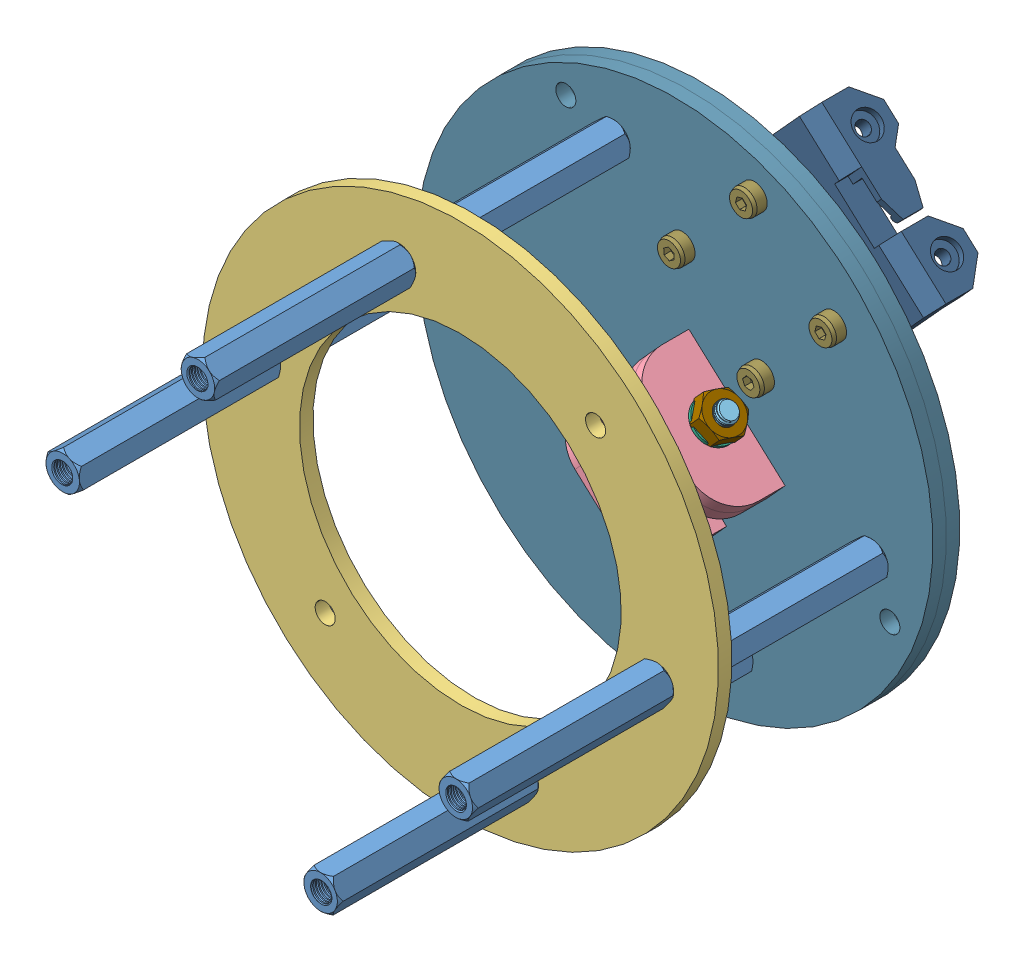
SolidWorks assembly RobotBaseAX12, configuration Default. Lengths in mm.
Overall size (108.77 108.77 76.29).
45 component instances, 15 part files, 103 mates.
Components (placement in the parent):
- M3Spacer30-1: M3Spacer30 [Default] at (4.7282 -17.4075 3.4562) x (0.207823 -0.978166 0) z (-0.978166 -0.207823 0) size (6.28 30.59 5)
- M3ThreadRod-1: M3ThreadRod [Default] at (4.7282 -17.4075 23.9562) x (0.200571 -0.979679 0) z (-0.979679 -0.200571 0) size (3.13 20.14 3.46)
- MiddlePlate-1: MiddlePlate [Default] at (-4.4212 11.1633 35.4562) x (0.672277 0.7403 0) z (0 0 -1) size (77 77 2)
- M3ThreadRod-2: M3ThreadRod [Default] at (-33.7389 17.525 23.9562) x (0.697343 -0.716737 0) z (-0.716737 -0.697343 0) size (3.13 20.14 3.46)
- M3ThreadRod-3: M3ThreadRod [Default] at (-13.5706 39.734 23.9562) x (0.867995 0.496573 0) z (0.496573 -0.867995 0) size (3.13 20.14 3.46)
- M3ThreadRod-4: M3ThreadRod [Default] at (24.8965 4.8015 23.9562) x (0.97301 -0.230763 0) z (-0.230763 -0.97301 0) size (3.13 20.14 3.46)
- M3Spacer30-2: M3Spacer30 [Default] at (-13.5706 39.734 3.4562) x (0.207823 -0.978166 0) z (-0.978166 -0.207823 0) size (6.28 30.59 5)
- M3Spacer30-3: M3Spacer30 [Default] at (-33.7389 17.525 3.4562) x (0.207823 -0.978166 0) z (-0.978166 -0.207823 0) size (6.28 30.59 5)
- M3Spacer30-4: M3Spacer30 [Default] at (24.8965 4.8015 3.4562) x (0.207823 -0.978166 0) z (-0.978166 -0.207823 0) size (6.28 30.59 5)
- M3Spacer30-5: M3Spacer30 [Default] at (-33.7389 17.525 35.4562) x (-0.803339 -0.595522 0) z (-0.595522 0.803339 0) size (6.28 30.59 5)
- M3Spacer30-6: M3Spacer30 [Default] at (-13.5706 39.734 35.4562) x (-0.94995 -0.312401 0) z (-0.312401 0.94995 0) size (6.28 30.59 5)
- M3Spacer30-7: M3Spacer30 [Default] at (24.8965 4.8015 35.4562) x (0.47318 -0.880966 0) z (-0.880966 -0.47318 0) size (6.28 30.59 5)
- M3Spacer30-8: M3Spacer30 [Default] at (4.7282 -17.4075 35.4562) x (0.999987 -0.005046 0) z (-0.005046 -0.999987 0) size (6.28 30.59 5)
- BearingBase-1: BearingBase [Default] at (-3.893 4.605 6.9562) x (0.7403 -0.672277 0) z (-0.672277 -0.7403 0) size (19.4 14 2)
- BearingBase-2: BearingBase [Default] at (-5.2375 3.1244 6.9562) x (0.7403 -0.672277 0) z (-0.672277 -0.7403 0) size (19.4 14 2)
- BearingBase-3: BearingBase [Default] at (3.5021 12.7483 6.9562) x (-0.7403 0.672277 0) z (0.672277 0.7403 0) size (19.4 14 2)
- BearingBase-4: BearingBase [Default] at (2.1575 11.2677 6.9562) x (-0.7403 0.672277 0) z (0.672277 0.7403 0) size (19.4 14 2)
- M3x20-1: M3x20 [Default] at (-6.5821 1.6438 6.9562) x (-0.399144 0.362469 -0.8422) z (-0.62348 0.566192 0.539166) size (5.5 23.77 5.5)
- M3Washer-1: M3Washer [Default] at (-2.5484 6.0856 6.9562) x (-0.730674 0.663536 0.160736) z (-0.118993 0.108059 -0.986997) size (6 0.5 6)
- PlasticSpacer-1: PlasticSpacer [Default] at (-2.5484 6.0856 6.9562) x (-0.284902 0.258724 -0.92298) z (-0.683282 0.620498 0.384847) size (6 2 6)
- pulley-1: pulley [Default] at (0.4768 9.4169 6.9562) x (-0.418707 0.380234 0.824686) z (0.610515 -0.554418 0.565591) size (12 4 12)
- M3Washer-2: M3Washer [Default] at (0.4768 9.4169 6.9562) x (0.735393 -0.667821 -0.114942) z (0.085091 -0.077273 0.993372) size (6 0.5 6)
- PlasticSpacer-3: PlasticSpacer [Default] at (2.1575 11.2677 6.9562) x (0.683126 -0.620357 -0.385352) z (-0.285276 0.259063 -0.92277) size (6 2 6)
- M3Nut-1: M3Nut [Default] at (4.8466 14.2289 6.9562) x (0.508771 -0.462022 0.726421) z (-0.53777 0.488356 0.68725) size (6.35 2.7 5.5)
- M3Washer-3: M3Washer [Default] at (4.8466 14.2289 6.9562) x (0.506448 -0.459913 -0.729377) z (0.539957 -0.490343 0.684112) size (6 0.5 6)
- AX12Base-1: AX12Base [Default] at (7.9887 31.5224 -0.5438) x (-0.7403 0.672277 0) z (-0.672277 -0.7403 0) size (25 9 38)
- M2Nut-1: M2Nut [Default] at (7.4445 42.823 -4.5438) x (-0.340986 0.940068 0) z (0.940068 0.340986 0) size (4.58 1.66 4.98)
- M2x8-1: M2x8 [Default] at (7.4445 42.823 3.4562) x (-0.96159 -0.27449 0) z (-0.27449 0.96159 0) size (3.8 10 3.8)
- M2Nut-2: M2Nut [Default] at (8.5328 20.2218 -4.5438) x (0.64363 0.765337 0) z (0.765337 -0.64363 0) size (4.58 1.66 4.98)
- M2Nut-3: M2Nut [Default] at (-3.312 30.9782 -4.5438) x (0.64363 0.765337 0) z (0.765337 -0.64363 0) size (4.58 1.66 4.98)
- M2Nut-4: M2Nut [Default] at (19.2893 32.0666 -4.5438) x (0.64363 0.765337 0) z (0.765337 -0.64363 0) size (4.58 1.66 4.98)
- M2x8-2: M2x8 [Default] at (8.5328 20.2218 3.4562) x (-0.634736 -0.772729 0) z (-0.772729 0.634736 0) size (3.8 10 3.8)
- M2x8-3: M2x8 [Default] at (-3.312 30.9782 3.4562) x (0.897196 -0.441632 0) z (-0.441632 -0.897196 0) size (3.8 10 3.8)
- M2x8-4: M2x8 [Default] at (19.2893 32.0666 3.4562) x (0.715995 -0.698105 0) z (-0.698105 -0.715995 0) size (3.8 10 3.8)
- M3Washer-4: M3Washer [Default] at (4.7282 -17.4075 -0.5438) x (-0.207823 0.978166 0) z (-0.978166 -0.207823 0) size (6 0.5 6)
- M3x10-1: M3x10 [Default] at (4.7282 -17.4075 -1.0438) x (0.990322 -0.138791 0) z (0.138791 0.990322 0) size (5.5 13.21 5.5)
- M3x10-2: M3x10 [Default] at (-13.5706 39.734 -1.0438) x (-0.982342 -0.187094 0) z (0.187094 -0.982342 0) size (5.5 13.21 5.5)
- M3x10-3: M3x10 [Default] at (-33.7389 17.525 -1.0438) x (-0.885366 0.464894 0) z (-0.464894 -0.885366 0) size (5.5 13.21 5.5)
- M3x10-4: M3x10 [Default] at (24.8965 4.8015 -1.0438) x (-0.753911 0.656976 0) z (-0.656976 -0.753911 0) size (5.5 13.21 5.5)
- M3Washer-5: M3Washer [Default] at (24.8965 4.8015 -0.5438) x (-0.207823 0.978166 0) z (-0.978166 -0.207823 0) size (6 0.5 6)
- M3Washer-6: M3Washer [Default] at (-13.5706 39.734 -0.5438) x (-0.207823 0.978166 0) z (-0.978166 -0.207823 0) size (6 0.5 6)
- M3Washer-7: M3Washer [Default] at (-33.7389 17.525 -0.5438) x (-0.207823 0.978166 0) z (-0.978166 -0.207823 0) size (6 0.5 6)
- BottomPlateAX12-1: BottomPlateAX12 [Default] at (-4.4755 11.2126 -0.5438) x (0.672277 0.7403 0) z (0 0 1) size (77 77 2)
- BottomPlateAX12-2: BottomPlateAX12 [Default] at (-4.4755 11.2126 1.4562) x (0.672277 0.7403 0) z (0 0 1) size (77 77 2)
- PCBMount-1: PCBMount [Default] at (-18.642 5.8415 -7.5438) x (0.7403 -0.672277 0) z (0.672277 0.7403 0) size (31.5 14 2)
Mates (geometry in assembly coordinates):
- Concentric1: concentric anti-aligned: circle of M3Spacer30-1; circle of MiddlePlate-1
- Concentric2: concentric anti-aligned: circle of MiddlePlate-1; circle of M3Spacer30-4
- Concentric3: concentric anti-aligned: circle of MiddlePlate-1; circle of M3Spacer30-3
- Concentric4: concentric anti-aligned: circle of MiddlePlate-1; circle of M3Spacer30-2
- Concentric5: concentric aligned: circle of M3ThreadRod-4; circle of M3Spacer30-4
- Concentric7: concentric anti-aligned: circle of M3ThreadRod-3; circle of M3Spacer30-2
- Concentric8: concentric aligned: circle of M3ThreadRod-2; circle of M3Spacer30-3
- Concentric9: concentric aligned: circle of M3Spacer30-1; circle of M3ThreadRod-1
- Distance5: distance = 10 mm aligned: plane of M3ThreadRod-1 through (4.7282 -17.4075 43.4562) normal (0 0 1); plane of M3Spacer30-1 through (4.7282 -17.4075 33.4562) normal (0 0 1)
- Distance6: distance = 10 mm aligned: plane of M3ThreadRod-2 through (-33.7389 17.525 43.4562) normal (0 0 1); plane of M3Spacer30-3 through (-33.7389 17.525 33.4562) normal (0 0 1)
- Distance7: distance = 10 mm aligned: plane of M3ThreadRod-3 through (-13.5706 39.734 43.4562) normal (0 0 1); plane of M3Spacer30-2 through (-13.5706 39.734 33.4562) normal (0 0 1)
- Distance8: distance = 10 mm aligned: plane of M3ThreadRod-4 through (24.8965 4.8015 43.4562) normal (0 0 1); plane of M3Spacer30-4 through (24.8965 4.8015 33.4562) normal (0 0 1)
- Coincident3: coincident anti-aligned: plane of M3Spacer30-1 through (4.7282 -17.4075 33.4562) normal (0 0 1); plane of MiddlePlate-1 through (-4.4212 11.1633 33.4562) normal (0 0 -1)
- Coincident4: coincident anti-aligned: plane of MiddlePlate-1 through (-4.4212 11.1633 33.4562) normal (0 0 -1); plane of M3Spacer30-4 through (24.8965 4.8015 33.4562) normal (0 0 1)
- Coincident5: coincident anti-aligned: plane of MiddlePlate-1 through (-4.4212 11.1633 33.4562) normal (0 0 -1); plane of M3Spacer30-2 through (-13.5706 39.734 33.4562) normal (0 0 1)
- Coincident6: coincident anti-aligned: plane of MiddlePlate-1 through (-4.4212 11.1633 33.4562) normal (0 0 -1); plane of M3Spacer30-3 through (-33.7389 17.525 33.4562) normal (0 0 1)
- Concentric10: concentric aligned: circle of M3ThreadRod-2; circle of M3Spacer30-5
- Concentric11: concentric aligned: circle of M3ThreadRod-3; circle of M3Spacer30-6
- Concentric12: concentric aligned: circle of M3ThreadRod-4; circle of M3Spacer30-7
- Concentric13: concentric aligned: circle of M3ThreadRod-1; circle of M3Spacer30-8
- Coincident8: coincident anti-aligned: plane of MiddlePlate-1 through (-4.4212 11.1633 35.4562) normal (0 0 1); plane of M3Spacer30-5 through (-33.7389 17.525 35.4562) normal (0 0 -1)
- Coincident9: coincident anti-aligned: plane of MiddlePlate-1 through (-4.4212 11.1633 35.4562) normal (0 0 1); plane of M3Spacer30-6 through (-13.5706 39.734 35.4562) normal (0 0 -1)
- Coincident10: coincident anti-aligned: plane of MiddlePlate-1 through (-4.4212 11.1633 35.4562) normal (0 0 1); plane of M3Spacer30-7 through (24.8965 4.8015 35.4562) normal (0 0 -1)
- Coincident11: coincident anti-aligned: plane of MiddlePlate-1 through (-4.4212 11.1633 35.4562) normal (0 0 1); plane of M3Spacer30-8 through (4.7282 -17.4075 35.4562) normal (0 0 -1)
- Parallel3: parallel aligned: plane of BearingBase-1 through (-2.4984 0.637 7.4562) normal (-0.672277 -0.7403 0); plane of BearingBase-2 through (-3.843 -0.8436 7.4562) normal (-0.672277 -0.7403 0)
- Concentric18: concentric aligned: circle of BearingBase-1; circle of BearingBase-2
- Coincident14: coincident anti-aligned: plane of BearingBase-1 through (-2.4984 0.637 7.4562) normal (-0.672277 -0.7403 0); plane of BearingBase-2 through (-2.4984 0.637 7.4562) normal (0.672277 0.7403 0)
- Coincident16: coincident: point of BearingBase-1; point of BearingBase-2
- Concentric19: concentric aligned: circle of BearingBase-3; circle of BearingBase-4
- Coincident18: coincident: point of BearingBase-3; point of BearingBase-4
- Concentric21: concentric aligned: circle of BearingBase-2; circle of M3x20-1
- Coincident22: coincident anti-aligned: plane of BearingBase-2 through (-3.843 -0.8436 7.4562) normal (-0.672277 -0.7403 0); plane of M3x20-1 through (-6.5821 1.6438 6.9562) normal (0.672277 0.7403 0)
- Concentric22: concentric aligned: circle of M3x20-1; circle of PlasticSpacer-1
- Coincident23: coincident anti-aligned: plane of BearingBase-1 through (-1.1539 2.1176 7.4562) normal (0.672277 0.7403 0); plane of PlasticSpacer-1 through (-3.893 4.605 6.9562) normal (-0.672277 -0.7403 0)
- Concentric23: concentric anti-aligned: circle of M3Washer-1; circle of PlasticSpacer-1
- Coincident25: coincident anti-aligned: plane of M3Washer-1 through (-2.5484 6.0856 6.9562) normal (-0.672277 -0.7403 0); plane of PlasticSpacer-1 through (-2.5484 6.0856 6.9562) normal (0.672277 0.7403 0)
- Concentric24: concentric anti-aligned: circle of M3Washer-1; circle of pulley-1
- Coincident26: coincident anti-aligned: plane of M3Washer-1 through (-2.2123 6.4557 6.9562) normal (0.672277 0.7403 0); plane of pulley-1 through (-2.2123 6.4557 6.9562) normal (-0.672277 -0.7403 0)
- Concentric25: concentric anti-aligned: circle of pulley-1; circle of M3Washer-2
- Coincident27: coincident anti-aligned: plane of pulley-1 through (0.4768 9.4169 6.9562) normal (0.672277 0.7403 0); plane of M3Washer-2 through (0.4768 9.4169 6.9562) normal (-0.672277 -0.7403 0)
- Concentric26: concentric aligned: circle of pulley-1; circle of PlasticSpacer-3
- Coincident28: coincident anti-aligned: plane of M3Washer-2 through (0.813 9.7871 6.9562) normal (0.672277 0.7403 0); plane of PlasticSpacer-3 through (0.813 9.7871 6.9562) normal (-0.672277 -0.7403 0)
- Concentric27: concentric anti-aligned: circle of BearingBase-4; circle of PlasticSpacer-3
- Concentric28: concentric anti-aligned: circle of pulley-1; circle of M3Nut-1
- Concentric29: concentric anti-aligned: circle of pulley-1; circle of M3Washer-3
- Coincident33: coincident anti-aligned: plane of BearingBase-4 through (-0.5816 13.7551 7.4562) normal (-0.672277 -0.7403 0); plane of PlasticSpacer-3 through (2.1575 11.2677 6.9562) normal (0.672277 0.7403 0)
- Coincident34: coincident anti-aligned: plane of BearingBase-3 through (2.1075 16.7163 7.4562) normal (0.672277 0.7403 0); plane of M3Washer-3 through (4.8466 14.2289 6.9562) normal (-0.672277 -0.7403 0)
- Coincident35: coincident anti-aligned: plane of BearingBase-3 through (2.1075 16.7163 7.4562) normal (0.672277 0.7403 0); plane of M3Nut-1 through (4.8466 14.2289 6.9562) normal (-0.672277 -0.7403 0)
- Concentric37: concentric aligned: circle of AX12Base-1; circle of M2Nut-2
- Concentric38: concentric aligned: circle of AX12Base-1; circle of M2Nut-4
- Concentric39: concentric aligned: circle of AX12Base-1; circle of M2Nut-3
- Concentric40: concentric aligned: circle of AX12Base-1; circle of M2Nut-1
- Coincident42: coincident anti-aligned: plane of AX12Base-1 through (-5.0216 32.5308 -4.5438) normal (0.977257 -0.212059 0); plane of M2Nut-3 through (-5.0216 32.5308 -3.0438) normal (-0.977257 0.212059 0)
- Coincident43: coincident anti-aligned: plane of AX12Base-1 through (5.7348 44.3756 -4.5438) normal (0.30498 -0.952359 0); plane of M2Nut-1 through (7.9342 45.0799 -3.0438) normal (-0.30498 0.952359 0)
- Coincident44: coincident anti-aligned: plane of AX12Base-1 through (20.9989 30.514 -4.5438) normal (-0.977257 0.212059 0); plane of M2Nut-4 through (20.9989 30.514 -3.0438) normal (0.977257 -0.212059 0)
- Coincident45: coincident anti-aligned: plane of AX12Base-1 through (8.0431 17.9649 -4.5438) normal (-0.30498 0.952359 0); plane of M2Nut-2 through (8.0431 17.9649 -3.0438) normal (0.30498 -0.952359 0)
- Coincident46: coincident anti-aligned: plane of AX12Base-1 through (-4.5319 34.7877 -3.0438) normal (0 0 -1); plane of M2Nut-3 through (-3.312 30.9782 -3.0438) normal (0 0 1)
- Coincident47: coincident anti-aligned: plane of AX12Base-1 through (7.9342 45.0799 -3.0438) normal (0 0 -1); plane of M2Nut-1 through (7.4445 42.823 -3.0438) normal (0 0 1)
- Coincident48: coincident anti-aligned: plane of AX12Base-1 through (21.4887 32.7709 -3.0438) normal (0 0 -1); plane of M2Nut-4 through (19.2893 32.0666 -3.0438) normal (0 0 1)
- Coincident49: coincident anti-aligned: plane of AX12Base-1 through (10.7322 20.9261 -3.0438) normal (0 0 -1); plane of M2Nut-2 through (8.5328 20.2218 -3.0438) normal (0 0 1)
- Concentric41: concentric aligned: circle of M3x10-2; circle of M3Washer-6
- Concentric42: concentric aligned: circle of M3Washer-4; circle of M3x10-1
- Concentric43: concentric aligned: circle of M3x10-4; circle of M3Washer-5
- Concentric44: concentric aligned: circle of M3x10-3; circle of M3Washer-7
- Coincident63: coincident anti-aligned: plane of M3x10-2 through (-13.5706 39.734 -1.0438) normal (0 0 1); plane of M3Washer-6 through (-13.5706 39.734 -1.0438) normal (0 0 -1)
- Coincident64: coincident anti-aligned: plane of M3x10-4 through (24.8965 4.8015 -1.0438) normal (0 0 1); plane of M3Washer-5 through (24.8965 4.8015 -1.0438) normal (0 0 -1)
- Coincident65: coincident anti-aligned: plane of M3Washer-4 through (4.7282 -17.4075 -1.0438) normal (0 0 -1); plane of M3x10-1 through (4.7282 -17.4075 -1.0438) normal (0 0 1)
- Coincident66: coincident anti-aligned: plane of M3x10-3 through (-33.7389 17.525 -1.0438) normal (0 0 1); plane of M3Washer-7 through (-33.7389 17.525 -1.0438) normal (0 0 -1)
- Parallel4: parallel anti-aligned: plane of BottomPlateAX12-1 through (-4.4212 11.1633 1.4562) normal (0 0 1); plane of BottomPlateAX12-2 through (-4.4212 11.1633 1.4562) normal (0 0 -1)
- Concentric45: concentric aligned: circle of BottomPlateAX12-1; circle of BottomPlateAX12-2
- Concentric46: concentric aligned: circle of BottomPlateAX12-1; circle of BottomPlateAX12-2
- Coincident69: coincident anti-aligned: plane of BottomPlateAX12-1 through (-4.4212 11.1633 1.4562) normal (0 0 1); plane of BottomPlateAX12-2 through (-4.4212 11.1633 1.4562) normal (0 0 -1)
- Parallel5: parallel anti-aligned: plane of MiddlePlate-1 through (-4.4212 11.1633 33.4562) normal (0 0 -1); plane of BottomPlateAX12-2 through (-4.4212 11.1633 3.4562) normal (0 0 1)
- Concentric47: concentric anti-aligned: circle of AX12Base-1; circle of BottomPlateAX12-2
- Concentric48: concentric aligned: circle of AX12Base-1; circle of BottomPlateAX12-2
- Coincident72: coincident anti-aligned: plane of AX12Base-1 through (27.2945 31.2132 -0.5438) normal (0 0 1); plane of BottomPlateAX12-1 through (-4.4212 11.1633 -0.5438) normal (0 0 -1)
- Concentric50: concentric aligned: circle of M2x8-3; circle of BottomPlateAX12-2
- Concentric51: concentric aligned: circle of AX12Base-1; circle of M2x8-2
- Concentric52: concentric aligned: circle of M2x8-4; circle of BottomPlateAX12-2
- Coincident73: coincident anti-aligned: plane of M2x8-3 through (-3.312 30.9782 3.4562) normal (0 0 -1); plane of BottomPlateAX12-2 through (-4.4212 11.1633 3.4562) normal (0 0 1)
- Coincident75: coincident anti-aligned: plane of M2x8-4 through (19.2893 32.0666 3.4562) normal (0 0 -1); plane of BottomPlateAX12-2 through (-4.4212 11.1633 3.4562) normal (0 0 1)
- Concentric53: concentric anti-aligned: circle of AX12Base-1; circle of M2x8-1
- Coincident76: coincident anti-aligned: plane of M2x8-1 through (7.4445 42.823 3.4562) normal (0 0 -1); plane of BottomPlateAX12-2 through (-4.4212 11.1633 3.4562) normal (0 0 1)
- Coincident77: coincident anti-aligned: plane of M2x8-2 through (8.5328 20.2218 3.4562) normal (0 0 -1); plane of BottomPlateAX12-2 through (-4.4212 11.1633 3.4562) normal (0 0 1)
- Coincident78: coincident anti-aligned: plane of BearingBase-2 through (-10.8018 5.4758 -0.5438) normal (-0.7403 0.672277 0); plane of BottomPlateAX12-2 through (-8.1127 8.437 3.4562) normal (0.7403 -0.672277 0)
- Coincident79: coincident anti-aligned: plane of BearingBase-2 through (-3.843 -0.8436 7.4562) normal (-0.672277 -0.7403 0); plane of BottomPlateAX12-2 through (-10.8018 5.4758 3.4562) normal (0.672277 0.7403 0)
- Coincident80: coincident: point of BearingBase-2; point of BottomPlateAX12-1
- Concentric54: concentric anti-aligned: circle of M3Washer-6; circle of BottomPlateAX12-2
- Concentric55: concentric anti-aligned: circle of M3Washer-7; circle of BottomPlateAX12-2
- Concentric56: concentric anti-aligned: circle of M3Washer-5; circle of BottomPlateAX12-2
- Concentric57: concentric anti-aligned: circle of M3Washer-4; circle of BottomPlateAX12-2
- Concentric58: concentric aligned: circle of M3Spacer30-2; circle of BottomPlateAX12-2
- Concentric59: concentric aligned: circle of M3Spacer30-3; circle of BottomPlateAX12-2
- Coincident81: coincident anti-aligned: plane of M3Washer-7 through (-33.7389 17.525 -0.5438) normal (0 0 1); plane of BottomPlateAX12-1 through (-4.4212 11.1633 -0.5438) normal (0 0 -1)
- Coincident82: coincident anti-aligned: plane of M3Washer-4 through (4.7282 -17.4075 -0.5438) normal (0 0 1); plane of BottomPlateAX12-1 through (-4.4212 11.1633 -0.5438) normal (0 0 -1)
- Coincident83: coincident anti-aligned: plane of M3Washer-5 through (24.8965 4.8015 -0.5438) normal (0 0 1); plane of BottomPlateAX12-1 through (-4.4212 11.1633 -0.5438) normal (0 0 -1)
- Coincident84: coincident anti-aligned: plane of M3Washer-6 through (-13.5706 39.734 -0.5438) normal (0 0 1); plane of BottomPlateAX12-1 through (-4.4212 11.1633 -0.5438) normal (0 0 -1)
- Coincident85: coincident anti-aligned: plane of M3Spacer30-3 through (-33.7389 17.525 3.4562) normal (0 0 -1); plane of BottomPlateAX12-2 through (-4.4212 11.1633 3.4562) normal (0 0 1)
- Distance9: distance = 1 mm: point of assembly; point of BottomPlateAX12-1
- Coincident86: coincident aligned: plane of BearingBase-4 through (-0.7176 16.5803 -0.5438) normal (0 0 -1); plane of BottomPlateAX12-1 through (-4.4212 11.1633 -0.5438) normal (0 0 -1)
- Coincident87: coincident anti-aligned: plane of BottomPlateAX12-1 through (-28.9571 17.9105 1.4562) normal (-0.672277 -0.7403 0); plane of PCBMount-1 through (-25.9959 15.2214 -6.5438) normal (0.672277 0.7403 0)
- Coincident88: coincident aligned: plane of BottomPlateAX12-2 through (-4.4212 11.1633 3.4562) normal (0 0 1); plane of PCBMount-1 through (-5.6377 -3.2662 3.4562) normal (0 0 1)
- Coincident89: coincident anti-aligned: plane of BottomPlateAX12-1 through (-6.9823 -4.7468 1.4562) normal (-0.7403 0.672277 0); plane of PCBMount-1 through (-5.6377 -3.2662 -6.5438) normal (0.7403 -0.672277 0)
